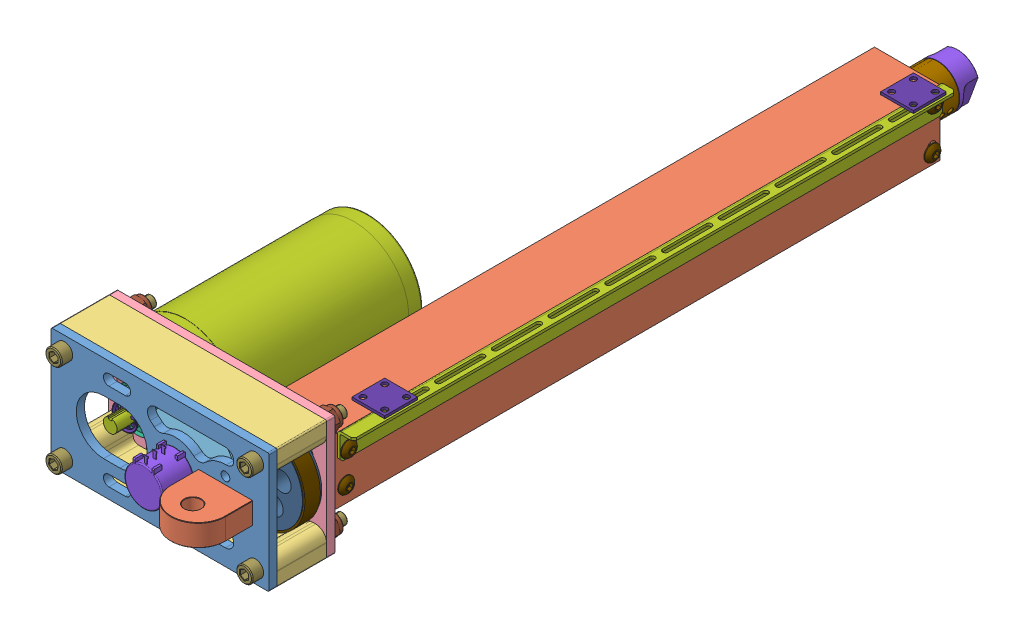
SolidWorks assembly 12in DART Accuator am-3072aDART12, configuration Default. Lengths in mm.
Overall size (130.39 70.08 458.28).
66 component instances, 36 part files, 0 mates.
Components (placement in the parent):
- DART Motor Module-1: DART Motor Module [Default] at (-21.729 72.3075 82.8213) size (127.28 70.08 189.4)
  - am-3250 DART Cap Plate-1: am-3250 DART Cap Plate [Default] at (-113.7808 -72.5058 -2.3813) x (1 0 0) z (0 -1 0) size (127 4.76 69.85)
  - am-3249 DART Pivot Block-1: am-3249 DART Pivot Block [Default] at (-28.0558 -43.9308 2.3813) size (31.75 12.7 31.75)
  - am-2650 Spacer-1: am-2650 Spacer [Default] at (-105.856 -64.581 -2.3813) x (1 0 0) z (0 0 -1) size (127 14.35 28.75)
  - am-2650 Spacer-2: am-2650 Spacer [Default] at (-105.856 -10.5806 -31.134) size (127 14.35 28.75)
  - am-3251 DART Base Plate-1: am-3251 DART Base Plate [Default] at (-113.7808 -72.5058 -35.8965) x (1 0 0) z (0 -1 0) size (127 4.76 69.85)
  - am-3267 Gear, 96T, 48dp, Acetal, Brass Hub, Set Screw-1: am-3267 Gear, 96T, 48dp, Acetal, Brass Hub, Set Screw [Default] at (-41.3146 -37.5808 -7.7025) x (1 0 0) z (0 1 0) size (50.8 9.53 50.8)
  - am-3263 12 Tooth Pulley-1: am-3263 12 Tooth Pulley [Default] at (-82.0308 -37.5808 -16.0718) x (-1 0 0) z (0 0 1) size (25.4 25.4 20.64)
  - CIM motor-1: CIM motor [Default] at (27.2654 -73.1408 -54.9465) x (0 1 0) z (0 0 1) size (64.01 64.01 154.93)
  - 10 turn potentiometer detail-1: 10 turn potentiometer detail [Default] at (-41.3146 -37.5808 2.6353) size (22.23 26.23 39.28)
  - am-1121-1: am-1121 [Default] at (-83.0308 -32.7808 -9.9846) x (1 0 0) z (0 0 -1) size (2 2 10)
  - 5-16 washer_1-1: 5-16 washer_1 [Default] at (-82.0308 -37.5808 -31.8326) size (17.53 17.53 1.47)
  - 250-20 Nylock Nut-1: 250-20 Nylock Nut [Default] at (-105.856 -10.5806 -35.8965) x (0.98377 -0.179436 0) z (0 0 -1) size (12.64 12.81 7.87)
  - 250-20 Nylock Nut-2: 250-20 Nylock Nut [Default] at (-105.856 -64.581 -35.8965) x (0.34754 0.937665 0) z (0 0 -1) size (12.64 12.81 7.87)
  - 250-20 Nylock Nut-3: 250-20 Nylock Nut [Default] at (5.2944 -64.581 -35.8965) x (0.98377 -0.179436 0) z (0 0 -1) size (12.64 12.81 7.87)
  - 250-20 Nylock Nut-4: 250-20 Nylock Nut [Default] at (5.2944 -10.5806 -35.8965) x (0.985812 0.167854 0) z (0 0 -1) size (12.64 12.81 7.87)
  - SHCS 14-20 x 2-1: SHCS 14-20 x 2 [Default] at (5.2944 -64.581 8.9345) x (1 0 0) z (0 -1 0) size (9.53 57.35 9.53)
  - SHCS 14-20 x 2-2: SHCS 14-20 x 2 [Default] at (-105.856 -10.5806 8.9345) x (1 0 0) z (0 -1 0) size (9.53 57.35 9.53)
  - SHCS 14-20 x 2-3: SHCS 14-20 x 2 [Default] at (-105.856 -64.581 8.9345) x (0.993224 -0.116212 0) z (-0.116212 -0.993224 0) size (9.53 57.35 9.53)
  - SHCS 14-20 x 2-4: SHCS 14-20 x 2 [Default] at (5.2944 -10.5806 8.9345) x (1 0 0) z (0 -1 0) size (9.53 57.35 9.53)
  - FHCS 10-32x0.625_SCHCSCREW 0.19-32x0.625x0.625-HX-C-1: FHCS 10-32x0.625_SCHCSCREW 0.19-32x0.625x0.625-HX-C [Default] at (-24.8808 -50.2808 -31.134) x (0 0 -1) z (0.923728 0.383049 0) size (15.88 10.21 10.21)
  - FHCS 10-32x0.625_SCHCSCREW 0.19-32x0.625x0.625-HX-C-2: FHCS 10-32x0.625_SCHCSCREW 0.19-32x0.625x0.625-HX-C [Default] at (0.5192 -50.2808 -31.134) x (0 0 -1) z (0.923728 0.383049 0) size (15.88 10.21 10.21)
  - FHCS 10-32x0.625_SCHCSCREW 0.19-32x0.625x0.625-HX-C-3: FHCS 10-32x0.625_SCHCSCREW 0.19-32x0.625x0.625-HX-C [Default] at (0.5192 -24.8808 -31.134) x (0 0 -1) z (0.923728 0.383049 0) size (15.88 10.21 10.21)
  - FHCS 10-32x0.625_SCHCSCREW 0.19-32x0.625x0.625-HX-C-4: FHCS 10-32x0.625_SCHCSCREW 0.19-32x0.625x0.625-HX-C [Default] at (-24.8808 -24.8808 -31.134) x (0 0 -1) z (0.923728 0.383049 0) size (15.88 10.21 10.21)
  - 10-32x0500_shcs_HX-SHCS 0.19-32x1.375x1-C-1: 10-32x0500_shcs_HX-SHCS 0.19-32x1.375x1-C [Default] at (-1.5128 -37.5808 -7.2073) x (0 0 1) z (-1 0 0) size (17.53 7.94 7.94)
  - 10-32x0500_shcs_HX-SHCS 0.19-32x1.375x1-C-2: 10-32x0500_shcs_HX-SHCS 0.19-32x1.375x1-C [Default] at (-22.8488 -37.5808 -7.2073) x (0 0 1) z (-1 0 0) size (17.53 7.94 7.94)
  - 10 Washer_Preferred Narrow FW 0.19-1: 10 Washer_Preferred Narrow FW 0.19 [Default] at (-82.0308 -62.9808 -31.134) x (0 0 -1) z (1 0 0) size (1.24 12.7 12.7)
  - 10 Washer_Preferred Narrow FW 0.19-2: 10 Washer_Preferred Narrow FW 0.19 [Default] at (-82.0308 -12.1808 -31.134) x (0 0 -1) z (1 0 0) size (1.24 12.7 12.7)
  - 10-32x0625_shcs_HX-SHCS 0.19-32x1.375x1-C-1: 10-32x0625_shcs_HX-SHCS 0.19-32x1.375x1-C [Default] at (-82.0308 -12.1808 -25.0634) x (0 0 -1) z (1 0 0) size (20.7 7.94 7.94)
  - 10-32x0625_shcs_HX-SHCS 0.19-32x1.375x1-C-2: 10-32x0625_shcs_HX-SHCS 0.19-32x1.375x1-C [Default] at (-82.0308 -62.9808 -25.0634) x (0 0 -1) z (1 0 0) size (20.7 7.94 7.94)
  - 8mm_spring_clip am-0033-1: 8mm_spring_clip am-0033 [Default] at (-82.0308 -37.5808 -9.7218) x (0 0 1) z (-1 0 0) size (1.12 14.83 14.83)
  - am-3274 HTD Timing Belt 240-5M-09-1: am-3274 HTD Timing Belt 240-5M-09 [Default] at (-12.4348 -37.5808 -18.6606) x (1 0 0) z (0 1 0) size (105.84 9 51.05)
- DART 12 Lead Screw Module-1: DART 12 Lead Screw Module [Default] at (-21.729 72.2567 104.8685) size (52.77 48.51 429.9) (flexible)
  - am-3260 Spacer-1: am-3260 Spacer [Default] at (-12.1808 -37.53 -73.8188) x (-0.979015 0.203789 0) z (0 0 1) size (12.7 12.7 6.35)
  - am-3260 Spacer-2: am-3260 Spacer [Default] at (-12.1808 -37.53 -51.4667) x (0.189554 -0.98187 0) z (0 0 -1) size (12.7 12.7 6.35)
  - am-3254 DART 12 Square Tube Rev1-1-1: am-3254 DART 12 Square Tube Rev1-1 [Default] at (-31.2943 -56.58 -416.7188) size (38.1 38.1 358.78)
  - am-3253 DART Bearing Block-1: am-3253 DART Bearing Block [Default] at (3.6307 -53.3415 -57.9438) x (-1 0 0) z (0 0 -1) size (31.62 31.62 25.4)
  - am-3259 DART Ram End Bearing-1: am-3259 DART Ram End Bearing [Default] at (-27.9923 -21.7185 -416.7188) x (0 -1 0) z (0 0 1) size (31.62 31.62 9.53)
  - am-3257 DART 12 Lead Screw-1: am-3257 DART 12 Lead Screw [Default] at (-12.1808 -37.53 -416.4457) x (0 0 1) z (-1 0 0) size (380.17 12.7 12.7)
  - am-3268 Gear, 14T, 48dp, Steel-1: am-3268 Gear, 14T, 48dp, Steel [Default] at (-12.1808 -37.53 -24.2126) x (1 0 0) z (0 1 0) size (7.41 8.89 7.41)
  - am-3252 DART 12 Sensor Bracket-1: am-3252 DART 12 Sensor Bracket [Default] at (6.8057 -19.2039 -416.7188) x (0 0 1) z (0 1 0) size (350.84 9.53 15.88)
  - am-3258 DART Ram Cap-1: am-3258 DART Ram Cap [Default] at (-12.1808 -37.53 -446.1954) x (0 0 1) z (-0.343416 -0.939183 0) size (24.59 25.4 25.4)
  - am-3256 DART Ram 12 Tube-1: am-3256 DART Ram 12 Tube [Default] at (-12.1808 -37.53 -434.3082) x (0.343416 0.939183 0) z (0 0 1) size (25.4 25.4 334.96)
  - am-3265 30T Pulley-1: am-3265 30T Pulley [Default] at (-12.1808 -37.53 -51.4667) x (1 0 0) z (0 -1 0) size (48.51 11.18 48.51)
  - am-1121-1: am-1121 [Default] at (-13.1648 -34.5262 -50.2908) size (2 2 10)
  - R3 Bearing-1: R3 Bearing [Default] at (-12.1808 -37.53 -24.2888) size (12.7 12.7 3.89)
  - Retaining Ring 3125_97431A310-1: Retaining Ring 3125_97431A310 [Default] at (-12.1808 -37.53 -408.6352) x (0 0 1) z (-0.983883 -0.178816 0) size (0.64 12.7 11.58)
  - Retaining Ring 3125_97431A310-2: Retaining Ring 3125_97431A310 [Default] at (-12.1808 -37.53 -38.5001) x (0 0 1) z (-1 0 0) size (0.64 12.7 11.58)
  - am-3255 DART Back Bearing-1: am-3255 DART Back Bearing [Default] at (3.6307 -21.7185 -89.8208) x (0 -1 0) z (1 0 0) size (31.63 9.53 31.62)
  - am-3262 DART Nut-1: am-3262 DART Nut [Default] at (-12.1808 -37.53 -54.3758) size (28.45 28.45 19.05)
  - 1614Z Bearing_smart-1: 1614Z Bearing_smart [Default] at (-12.1808 -37.53 -83.4707) x (0 0 1) z (-1 0 0) size (9.65 28.7 28.7)
  - 1614Z Bearing_smart-2: 1614Z Bearing_smart [Default] at (-12.1808 -37.53 -67.4688) x (0 0 1) z (-1 0 0) size (9.65 28.7 28.7)
  - 5-16 washer_1-1: 5-16 washer_1 [Default] at (-12.1808 -37.53 -40.2908) size (17.53 17.53 1.47)
  - 5-16 washer_1-2: 5-16 washer_1 [Default] at (-12.1808 -37.53 -408.3939) size (17.53 17.53 1.47)
  - 1875 dia 500 long 8-32_91259A166-1: 1875 dia 500 long 8-32_91259A166 [Default] at (-12.1808 -37.53 -20.4025) x (1 0 0) z (0 -1 0) size (7.94 21.71 7.94)
  - Hall Effect Sensor-1: Hall Effect Sensor [Default] at (-3.8623 -15.3685 -85.0583) x (0 0 -1) z (-1 0 0) size (19.05 2.79 19.05)
  - am-3255 DART Back Bearing-2: am-3255 DART Back Bearing [Default] at (3.6307 -21.7185 -397.6687) x (0 -1 0) z (1 0 0) size (31.63 9.53 31.62)
  - Hall Effect Sensor-2: Hall Effect Sensor [Default] at (-3.8623 -15.3685 -392.9062) x (0 0 -1) z (-1 0 0) size (19.05 2.79 19.05)
  - BHCS 10-32 x 0.375 phillips_SBHCSCREW 0.19-32x0.5-HX-C-1: BHCS 10-32 x 0.375 phillips_SBHCSCREW 0.19-32x0.5-HX-C [Default] at (9.3711 -47.055 -70.6438) x (-1 0 0) z (0 -0.924225 -0.381849) size (12.6 9.29 9.24)
  - BHCS 10-32 x 0.375 phillips_SBHCSCREW 0.19-32x0.5-HX-C-2: BHCS 10-32 x 0.375 phillips_SBHCSCREW 0.19-32x0.5-HX-C [Default] at (9.3711 -50.23 -411.9563) x (-1 0 0) z (0 -0.924225 -0.381849) size (12.6 9.29 9.24)
  - BHCS 10-32 x 0.375 phillips_SBHCSCREW 0.19-32x0.5-HX-C-3: BHCS 10-32 x 0.375 phillips_SBHCSCREW 0.19-32x0.5-HX-C [Default] at (10.8951 -28.005 -70.6438) x (-1 0 0) z (0 -0.924225 -0.381849) size (12.6 9.29 9.24)
  - BHCS 10-32 x 0.375 phillips_SBHCSCREW 0.19-32x0.5-HX-C-4: BHCS 10-32 x 0.375 phillips_SBHCSCREW 0.19-32x0.5-HX-C [Default] at (10.8951 -24.83 -411.9563) x (-1 0 0) z (0 -0.924225 -0.381849) size (12.6 9.29 9.24)
  - BHCS 10-32 x 0.375 phillips_SBHCSCREW 0.19-32x0.5-HX-C-5: BHCS 10-32 x 0.375 phillips_SBHCSCREW 0.19-32x0.5-HX-C [Default] at (-33.8597 -50.23 -411.9563) size (12.6 9.29 9.24)
  - BHCS 10-32 x 0.375 phillips_SBHCSCREW 0.19-32x0.5-HX-C-6: BHCS 10-32 x 0.375 phillips_SBHCSCREW 0.19-32x0.5-HX-C [Default] at (-33.8597 -24.83 -411.9563) size (12.6 9.29 9.24)
  - BHCS 10-32 x 0.375 phillips_SBHCSCREW 0.19-32x0.5-HX-C-7: BHCS 10-32 x 0.375 phillips_SBHCSCREW 0.19-32x0.5-HX-C [Default] at (-33.8597 -28.005 -70.6438) size (12.6 9.29 9.24)
  - BHCS 10-32 x 0.375 phillips_SBHCSCREW 0.19-32x0.5-HX-C-8: BHCS 10-32 x 0.375 phillips_SBHCSCREW 0.19-32x0.5-HX-C [Default] at (-33.8597 -47.055 -70.6438) size (12.6 9.29 9.24)
